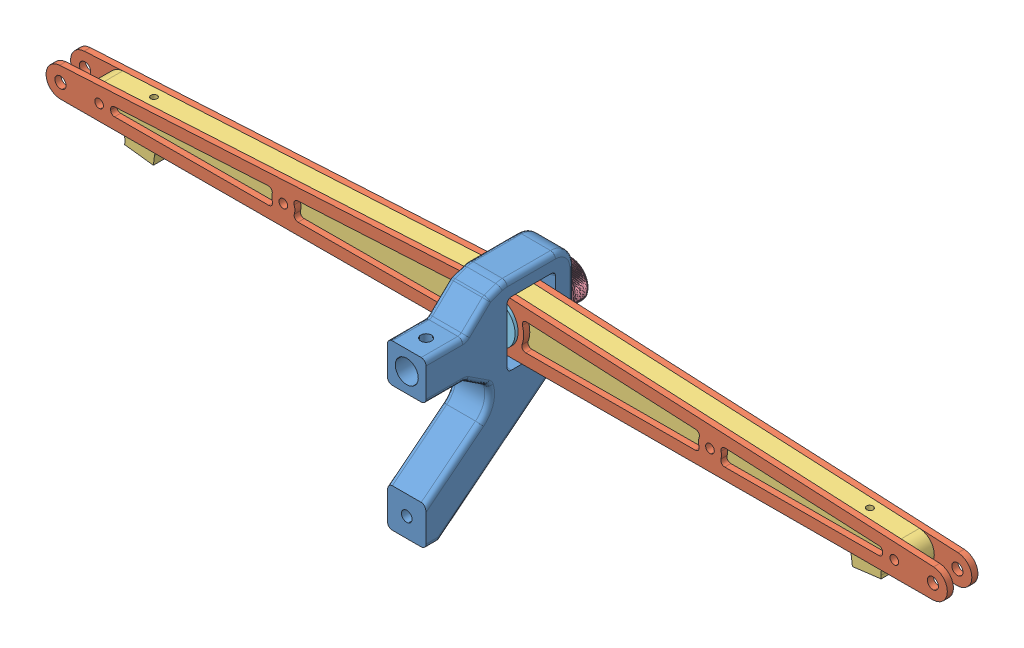
SolidWorks assembly UOR23-CNS-4-A-001_Swing_arm_assembly, configuration Default. Lengths in mm.
Overall size (467.09 99.5 85.3).
7 component instances, 5 part files, 14 mates.
Components (placement in the parent):
- UOR23-CNS-4-P-001_Swing_arm_support-1: UOR23-CNS-4-P-001_Swing_arm_support [Default] at origin size (20 99.5 72)
- UOR23-CNS-4-P-002_Swing_arm_plate-1: UOR23-CNS-4-P-002_Swing_arm_plate [Default] at (0 0 -59.2625) x (0.999996 0.002895 0) z (0.002895 -0.999996 0) size (467.01 3.17 26.73)
- UOR23-CNS-4-P-003_Swing_arm_spacer-1: UOR23-CNS-4-P-003_Swing_arm_spacer [Default] at (0 0 -59.2625) x (0.999996 0.002895 0) z (0.002895 -0.999996 0) size (428.06 9.53 35.64)
- UOR23-CNS-4-P-002_Swing_arm_plate-2: UOR23-CNS-4-P-002_Swing_arm_plate [Default] at (0 0 -46.5625) x (0.999996 0.002895 0) z (0.002895 -0.999996 0) size (467.01 3.17 26.73)
- 91259A489_Alloy Steel Shoulder Screw-1: 91259A489_Alloy Steel Shoulder Screw [91259A489] at (0 0 -84.9375) x (-0.923728 -0.383049 0) z (0 0 -1) size (19.05 19.05 59.62)
- 6294K445_Dry-Running MDS-Filled Nylon Sleeve Bearing (1)-1: 6294K445_Dry-Running MDS-Filled Nylon Sleeve Bearing (1) [6294K444] at (0 0 -64.025) x (0.999719 0.023711 0) z (0.023711 -0.999719 0) size (22.23 9.53 22.23)
- 6294K445_Dry-Running MDS-Filled Nylon Sleeve Bearing (1)-2: 6294K445_Dry-Running MDS-Filled Nylon Sleeve Bearing (1) [6294K444] at (0 0 -44.975) x (-0.932551 -0.361039 0) z (0.361039 -0.932551 0) size (22.23 9.53 22.23)
Mates (geometry in assembly coordinates):
- Concentric1: concentric anti-aligned: cylinder of UOR23-CNS-4-P-002_Swing_arm_plate-1 through (0 0 -62.4375) axis (0 0 1) radius 8; cylinder of UOR23-CNS-4-P-003_Swing_arm_spacer-1 through (0 0 -49.7375) axis (0 0 -1) radius 8
- Concentric2: concentric anti-aligned: cylinder of UOR23-CNS-4-P-003_Swing_arm_spacer-1 through (0 0 -49.7375) axis (0 0 -1) radius 8; cylinder of UOR23-CNS-4-P-002_Swing_arm_plate-2 through (0 0 -49.7375) axis (0 0 1) radius 8
- Coincident1: coincident anti-aligned: plane of UOR23-CNS-4-P-003_Swing_arm_spacer-1 through (226.0162 -5.2729 -49.7375) normal (0 0 1); plane of UOR23-CNS-4-P-002_Swing_arm_plate-2 through (-225.9819 -6.5815 -49.7375) normal (0 0 -1)
- Coincident2: coincident anti-aligned: plane of UOR23-CNS-4-P-002_Swing_arm_plate-1 through (-225.9819 -6.5815 -59.2625) normal (0 0 1); plane of UOR23-CNS-4-P-003_Swing_arm_spacer-1 through (226.0162 -5.2729 -59.2625) normal (0 0 -1)
- Coincident3: coincident aligned: plane of UOR23-CNS-4-P-003_Swing_arm_spacer-1 through (-225.9602 -14.0866 -49.7375) normal (0.002895 -0.999996 0); plane of UOR23-CNS-4-P-002_Swing_arm_plate-2 through (226.0379 -12.778 -49.7375) normal (0.002895 -0.999996 0)
- Coincident4: coincident aligned: plane of UOR23-CNS-4-P-002_Swing_arm_plate-1 through (226.0379 -12.778 -62.4375) normal (0.002895 -0.999996 0); plane of UOR23-CNS-4-P-003_Swing_arm_spacer-1 through (-225.9602 -14.0866 -49.7375) normal (0.002895 -0.999996 0)
- Concentric3: concentric aligned: cylinder of UOR23-CNS-4-P-001_Swing_arm_support-1 through (0 0 0) axis (0 0 -1) radius 5.9563; cylinder of UOR23-CNS-4-P-003_Swing_arm_spacer-1 through (0 0 -49.7375) axis (0 0 -1) radius 8
- Width1: width anti-aligned: plane of UOR23-CNS-4-P-001_Swing_arm_support-1 through (10 0 -37) normal (0 0 -1); plane of UOR23-CNS-4-P-001_Swing_arm_support-1 through (10 0 -62) normal (0 0 1); plane of UOR23-CNS-4-P-002_Swing_arm_plate-2 through (-225.9819 -6.5815 -46.5625) normal (0 0 1); plane of UOR23-CNS-4-P-002_Swing_arm_plate-1 through (-225.9819 -6.5815 -62.4375) normal (0 0 -1)
- Concentric4: concentric anti-aligned: cylinder of UOR23-CNS-4-P-001_Swing_arm_support-1 through (0 0 0.001) axis (0 0 -1) radius 6.45; cylinder of 91259A489_Alloy Steel Shoulder Screw-1 through (0 0 -26.2) axis (0 0 1) radius 6.35
- Coincident5: coincident anti-aligned: plane of UOR23-CNS-4-P-001_Swing_arm_support-1 through (10 0 -77) normal (0 0 -1); plane of 91259A489_Alloy Steel Shoulder Screw-1 through (3.6485 -8.7985 -77) normal (0 0 1)
- Concentric5: concentric anti-aligned: cylinder of 91259A489_Alloy Steel Shoulder Screw-1 through (0 0 -26.2) axis (0 0 1) radius 6.35; cylinder of 6294K445_Dry-Running MDS-Filled Nylon Sleeve Bearing (1)-1 through (0 0 -54.5) axis (0 0 -1) radius 7.9375
- Coincident6: coincident anti-aligned: plane of UOR23-CNS-4-P-002_Swing_arm_plate-1 through (-225.9819 -6.5815 -62.4375) normal (0 0 -1); plane of 6294K445_Dry-Running MDS-Filled Nylon Sleeve Bearing (1)-1 through (0 0 -62.4375) normal (0 0 1)
- Concentric6: concentric aligned: cylinder of 91259A489_Alloy Steel Shoulder Screw-1 through (0 0 -26.2) axis (0 0 1) radius 6.35; cylinder of 6294K445_Dry-Running MDS-Filled Nylon Sleeve Bearing (1)-2 through (0 0 -54.5) axis (0 0 1) radius 7.9375
- Coincident7: coincident anti-aligned: plane of UOR23-CNS-4-P-002_Swing_arm_plate-2 through (-225.9819 -6.5815 -46.5625) normal (0 0 1); plane of 6294K445_Dry-Running MDS-Filled Nylon Sleeve Bearing (1)-2 through (0 0 -46.5625) normal (0 0 -1)
